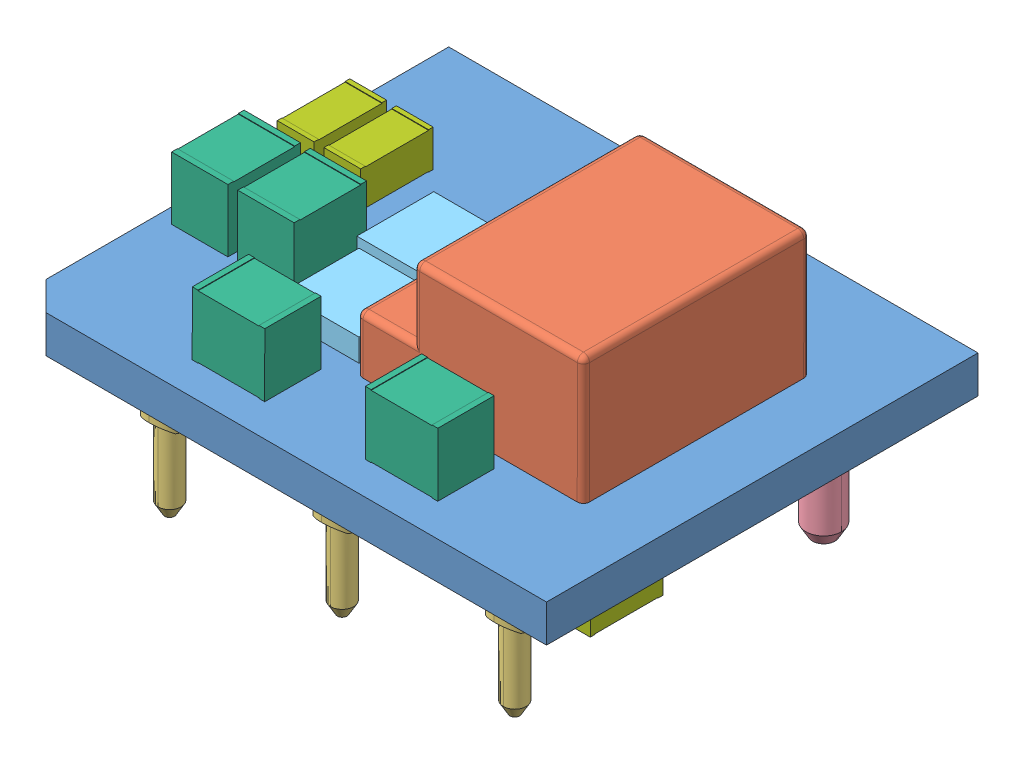
SolidWorks assembly i3a_full, configuration Default. Lengths in mm.
Overall size (23.37 13.23 19.05).
25 component instances, 9 part files, 0 mates.
Components (placement in the parent):
- i3a_standard_asm.stp-1: i3a_standard_asm.stp [Default] at origin size (23.37 13.23 19.05)
  - I3A_PCB.stp-1: I3A_PCB.stp [Default] at (-3.5174 0.0077 -6.974) x (1 -0.000726 0) z (0 0 1) size (23.37 1.65 19.05)
  - I3A_OUTPUT_INDUCTOR.stp-1: I3A_OUTPUT_INDUCTOR.stp [Default] at (0.2967 5.656 -6.9486) x (-1 0.000726 0) z (-0.000726 -1 0) size (10 10.01 5.6)
  - ZP00166_01-.stp-1: ZP00166_01-.stp [Default] at (-11.1374 0.0133 -0.116) x (0 0 1) z (1 -0.000726 0) size (1.83 6.99 1.83)
  - ZP00166_01-.stp-2: ZP00166_01-.stp [Default] at (-3.5174 0.0077 -0.116) x (0 0 1) z (1 -0.000726 0) size (1.83 6.99 1.83)
  - ZP00166_01-.stp-3: ZP00166_01-.stp [Default] at (4.1026 0.0022 -0.116) x (0 0 1) z (1 -0.000726 0) size (1.83 6.99 1.83)
  - ZP00167_01-.stp-1: ZP00167_01-.stp [Default] at (-11.1374 0.0133 -13.7558) x (1 -0.000726 0) z (0 0 -1) size (2.6 6.99 2.59)
  - ZP00167_01-.stp-2: ZP00167_01-.stp [Default] at (4.1026 0.0022 -13.7558) x (1 -0.000726 0) z (0 0 -1) size (2.6 6.99 2.59)
  - ZP00166_01-.stp-4: ZP00166_01-.stp [Default] at (-7.3274 0.0105 -13.7558) x (1 -0.000726 0) z (0 0 -1) size (1.83 6.99 1.83)
  - ZP00166_01-.stp-5: ZP00166_01-.stp [Default] at (-3.5174 0.0077 -13.7558) x (1 -0.000726 0) z (0 0 -1) size (1.83 6.99 1.83)
  - ZP00166_01-.stp-6: ZP00166_01-.stp [Default] at (0.2926 0.005 -13.7558) x (1 -0.000726 0) z (0 0 -1) size (1.83 6.99 1.83)
  - I6A_HIGH_SIDE_FET.stp-1: I6A_HIGH_SIDE_FET.stp [Default] at (-7.3008 1.6615 -7.9392) x (1 -0.000726 0) z (0 0 1) size (3.4 1 3.4)
  - I6A_HIGH_SIDE_FET.stp-2: I6A_HIGH_SIDE_FET.stp [Default] at (-6.7928 1.6611 -4.1292) x (1 -0.000726 0) z (0 0 1) size (3.4 1 3.4)
  - 1210_CAP_COLOR.stp-1: 1210_CAP_COLOR.stp [Default] at (-13.2902 1.6404 -5.196) x (0 0 1) z (-1 0.000726 0) size (3.2 2.79 2.49)
  - 1210_CAP_COLOR.stp-2: 1210_CAP_COLOR.stp [Default] at (-10.3702 1.6383 -5.196) x (0 0 1) z (-1 0.000726 0) size (3.2 2.79 2.49)
  - 1206_CAP_COLOR.stp-1: 1206_CAP_COLOR.stp [Default] at (-13.7302 1.6661 -9.869) x (0 0 1) z (-1 0.000726 0) size (3.2 1.63 1.63)
  - 1206_CAP_COLOR.stp-2: 1206_CAP_COLOR.stp [Default] at (-11.6702 1.6647 -9.869) x (0 0 1) z (-1 0.000726 0) size (3.2 1.63 1.63)
  - 1206_CAP_COLOR.stp-3: 1206_CAP_COLOR.stp [Default] at (-12.4613 0.0396 -11.139) x (1 -0.000726 0) z (0 0 -1) size (3.2 1.63 1.63)
  - 1206_CAP_COLOR.stp-4: 1206_CAP_COLOR.stp [Default] at (-12.4613 0.0396 -9.079) x (1 -0.000726 0) z (0 0 -1) size (3.2 1.63 1.63)
  - 1206_CAP_COLOR.stp-5: 1206_CAP_COLOR.stp [Default] at (-12.4613 0.0396 -7.019) x (1 -0.000726 0) z (0 0 -1) size (3.2 1.63 1.63)
  - 1206_CAP_COLOR.stp-6: 1206_CAP_COLOR.stp [Default] at (6.4186 0.0259 -1.919) x (0 0 1) z (1 -0.000726 0) size (3.2 1.63 1.63)
  - 0805_CAP.stp-1: 0805_CAP.stp [Default] at (5.6986 0.0264 -9.109) x (0 0 1) z (1 -0.000726 0) size (2.01 1.45 1.24)
  - I6A_CONTROL_IC2.stp-1: I6A_CONTROL_IC2.stp [Default] at (0.9786 0.0045 -8.089) x (0 0 -1) z (-1 0.000726 0) size (4.65 1 3.65)
  - 1210_CAP_COLOR.stp-3: 1210_CAP_COLOR.stp [Default] at (0.3198 1.6559 -0.139) x (1 -0.000726 0) z (0 0 1) size (3.2 2.79 2.49)
  - 1210_CAP_COLOR.stp-4: 1210_CAP_COLOR.stp [Default] at (-7.3002 1.6615 -0.119) x (1 -0.000726 0) z (0 0 1) size (3.2 2.79 2.49)
